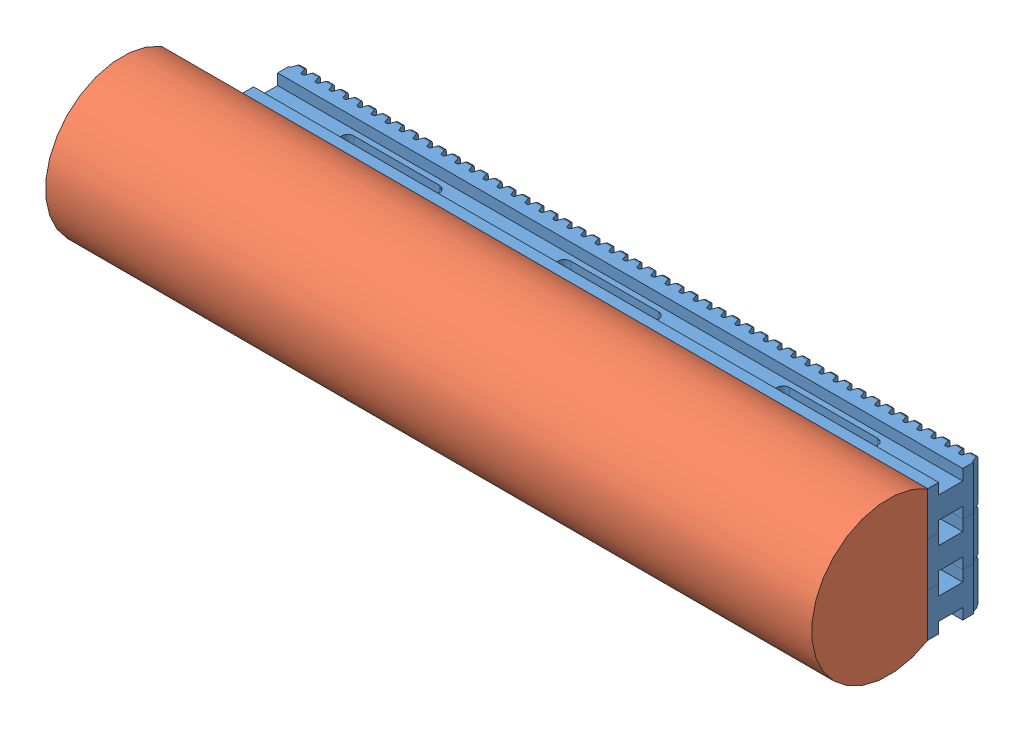
SolidWorks assembly Assem1, configuration Default. Lengths in mm.
Overall size (350 75.31 81.39).
4 component instances, 2 part files, 9 mates.
Components (placement in the parent):
- Part1-4: Part1 [Default] at (160.7023 74.1243 36.9954) size (313 20 25)
- Part1-5: Part1 [Default] at (160.7023 94.1243 36.9954) size (313 20 25)
- Part1-6: Part1 [Default] at (160.7023 54.1243 36.9954) size (313 20 25)
- [SPCN] Actuator Rod-1: [SPCN] Actuator Rod [Default] at (-35.6477 128.1243 129.0232) x (0 0.994858 0.101282) z (1 0 0) size (70 55.97 350)
Mates (geometry in assembly coordinates):
- Coincident4: coincident anti-aligned: plane of Part1-4 through (160.7023 118.1243 36.9954) normal (0 -1 0); plane of Part1-6 through (160.7023 118.1243 36.9954) normal (0 1 0)
- Coincident5: coincident aligned: plane of Part1-4 through (314.3523 138.1243 110.9954) normal (0 0 1); plane of Part1-6 through (314.3523 118.1243 110.9954) normal (0 0 1)
- Coincident6: coincident aligned: plane of Part1-4 through (314.3523 138.1243 85.9954) normal (1 0 0); plane of Part1-6 through (314.3523 118.1243 85.9954) normal (1 0 0)
- Coincident7: coincident anti-aligned: plane of Part1-4 through (160.7023 138.1243 36.9954) normal (0 1 0); plane of Part1-5 through (160.7023 138.1243 36.9954) normal (0 -1 0)
- Coincident8: coincident aligned: plane of Part1-4 through (314.3523 138.1243 110.9954) normal (0 0 1); plane of Part1-5 through (314.3523 158.1243 110.9954) normal (0 0 1)
- Coincident9: coincident aligned: plane of Part1-4 through (314.3523 138.1243 85.9954) normal (1 0 0); plane of Part1-5 through (314.3523 158.1243 85.9954) normal (1 0 0)
- Coincident11: coincident anti-aligned: plane of Part1-4 through (314.3523 138.1243 110.9954) normal (0 0 1); plane of [SPCN] Actuator Rod-1 through (314.3523 158.1243 110.9954) normal (0 0 -1)
- Coincident12: coincident aligned: plane of Part1-4 through (314.3523 138.1243 85.9954) normal (1 0 0); plane of [SPCN] Actuator Rod-1 through (314.3523 128.1243 129.0232) normal (1 0 0)
- Coincident13: coincident aligned: line of Part1-5 through (314.3523 158.1243 110.9954) axis (-1 0 0); line of [SPCN] Actuator Rod-1 through (314.3523 158.1243 110.9954) axis (-1 0 0)
